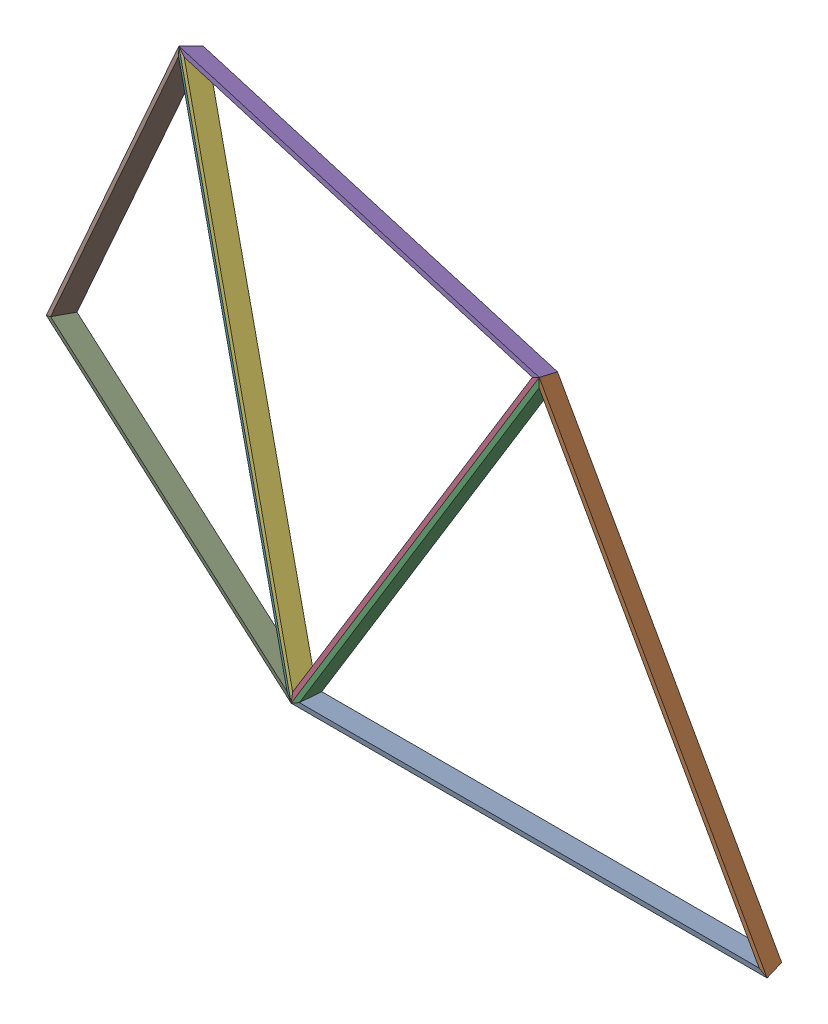
SolidWorks assembly hex-half_1, configuration Default. Lengths in mm.
Overall size (6417.48 4846.04 3982.2).
12 component instances, 3 part files, 0 mates.
Components (placement in the parent):
- hex_1_1-1: hex_1_1 [Default] at origin size (3132.81 3334.25 2398.03)
  - dome-hex_A_1-1: dome-hex_A_1 [Default] at (-54.8338 723.4273 -6076.5179) x (-0.072057 -0.575985 0.814278) z (-0.865209 0.442256 0.236269) size (283.93 1314.1 2231.51)
  - dome-hex_B_1-1: dome-hex_B_1 [Default] at (-54.8338 723.4273 -6076.5179) x (-0.072057 -0.575985 0.814278) z (-0.865209 0.442256 0.236269) size (1246.15 959.88 2041.73)
  - dome-hex_C_1-1: dome-hex_C_1 [Default] at (-54.8338 723.4273 -6076.5179) x (-0.072057 -0.575985 0.814278) z (-0.865209 0.442256 0.236269) size (1432 2214.62 244.45)
- hex_1_1-2: hex_1_1 [Default] at (-643.6223 1147.3164 0) x (0.52126 0.853398 0) z (-0.200359 0.122381 0.972049) size (3132.81 3334.25 2398.03)
  - dome-hex_A_1-1: dome-hex_A_1 [Default] at (-54.8338 723.4273 -6076.5179) x (-0.072057 -0.575985 0.814278) z (-0.865209 0.442256 0.236269) size (283.93 1314.1 2231.51)
  - dome-hex_B_1-1: dome-hex_B_1 [Default] at (-54.8338 723.4273 -6076.5179) x (-0.072057 -0.575985 0.814278) z (-0.865209 0.442256 0.236269) size (1246.15 959.88 2041.73)
  - dome-hex_C_1-1: dome-hex_C_1 [Default] at (-54.8338 723.4273 -6076.5179) x (-0.072057 -0.575985 0.814278) z (-0.865209 0.442256 0.236269) size (1432 2214.62 244.45)
- hex_1_1-3: hex_1_1 [Default] at (-1930.867 1179.3851 -269.3649) x (-0.436219 0.877251 -0.200359) z (-0.400718 0.009983 0.916147) size (3132.81 3334.25 2398.03)
  - dome-hex_A_1-1: dome-hex_A_1 [Default] at (-54.8338 723.4273 -6076.5179) x (-0.072057 -0.575985 0.814278) z (-0.865209 0.442256 0.236269) size (283.93 1314.1 2231.51)
  - dome-hex_B_1-1: dome-hex_B_1 [Default] at (-54.8338 723.4273 -6076.5179) x (-0.072057 -0.575985 0.814278) z (-0.865209 0.442256 0.236269) size (1246.15 959.88 2041.73)
  - dome-hex_C_1-1: dome-hex_C_1 [Default] at (-54.8338 723.4273 -6076.5179) x (-0.072057 -0.575985 0.814278) z (-0.865209 0.442256 0.236269) size (1432 2214.62 244.45)
